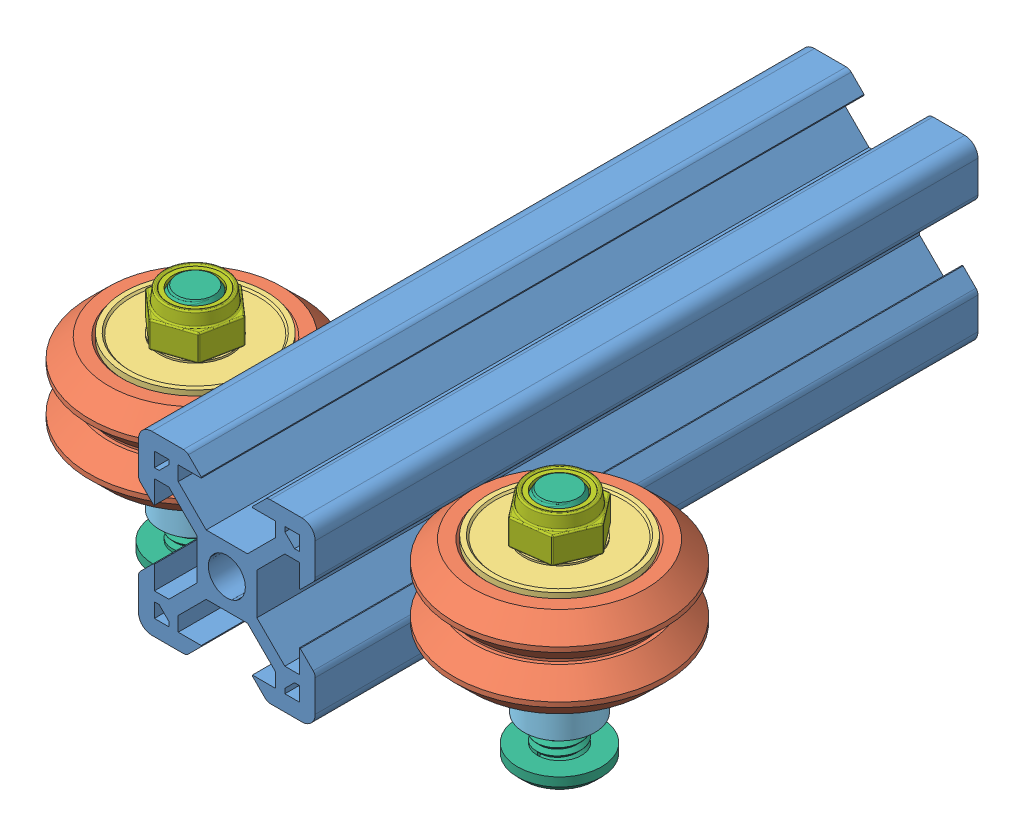
SolidWorks assembly 20 x 20 with wheels, configuration Default. Lengths in mm.
Overall size (66.47 27.2 75).
17 component instances, 7 part files, 3 mates.
Components (placement in the parent):
- 20mm x 20mm x75mm-1: 20mm x 20mm x75mm [Default<As Machined>] at (-32.4939 -14.3937 64.4255) size (20 20 75)
- V-Slot Delrin Dual Wheel Assembly-1: V-Slot Delrin Dual Wheel Assembly [Default] at (-59.3379 -25.4505 35.7981) x (0.980747 0 -0.195284) z (0 -1 0) size (23.89 23.89 27.2)
  - Delrin Dual V-Wheel-1: Delrin Dual V-Wheel [Default] at (4.1766 13.0717 -11.0846) size (23.89 23.89 10.23)
  - Precision Ball Bearing-1: Precision Ball Bearing [Default] at (4.1766 13.0717 -8.0846) x (0 0 -1) z (1 0 0) size (5 16 16)
  - Precision Ball Bearing-2: Precision Ball Bearing [Default] at (4.1766 13.0717 -14.0846) x (0 0 -1) z (1 0 0) size (5 16 16)
  - 5mm Precision Washer-1: 5mm Precision Washer [Default] at (4.1766 13.0717 -11.5846) x (0 0 1) z (-1 0 0) size (1 10 10)
  - .25 Inch Aluminum Spacer-1: .25 Inch Aluminum Spacer [Default] at (4.1766 13.0717 0.7654) x (0 0 -1) z (1 0 0) size (6.35 8 8)
  - 5mm Low Profile Socket Head Screw - Multiple Lengths-1: 5mm Low Profile Socket Head Screw - Multiple Lengths [Default] at (4.1766 13.0717 5.5154) x (0 0 -1) z (1 0 0) size (27.2 9.5 9.5)
  - Nylon Insert Hex Locknut 5mm-1: Nylon Insert Hex Locknut 5mm [Default] at (4.1766 13.0717 -16.5846) x (-0.923728 -0.383049 0) z (0 0 -1) size (7.68 8.82 4.5)
- V-Slot Delrin Dual Wheel Assembly-2: V-Slot Delrin Dual Wheel Assembly [Default] at (-16.3927 -25.4505 33.9845) x (1 0 0) z (0 -1 0) size (23.89 23.89 27.2)
  - Delrin Dual V-Wheel-1: Delrin Dual V-Wheel [Default] at (4.1766 13.0717 -11.0846) size (23.89 23.89 10.23)
  - Precision Ball Bearing-1: Precision Ball Bearing [Default] at (4.1766 13.0717 -8.0846) x (0 0 -1) z (1 0 0) size (5 16 16)
  - Precision Ball Bearing-2: Precision Ball Bearing [Default] at (4.1766 13.0717 -14.0846) x (0 0 -1) z (1 0 0) size (5 16 16)
  - 5mm Precision Washer-1: 5mm Precision Washer [Default] at (4.1766 13.0717 -11.5846) x (0 0 1) z (-1 0 0) size (1 10 10)
  - .25 Inch Aluminum Spacer-1: .25 Inch Aluminum Spacer [Default] at (4.1766 13.0717 0.7654) x (0 0 -1) z (1 0 0) size (6.35 8 8)
  - 5mm Low Profile Socket Head Screw - Multiple Lengths-1: 5mm Low Profile Socket Head Screw - Multiple Lengths [Default] at (4.1766 13.0717 5.5154) x (0 0 -1) z (1 0 0) size (27.2 9.5 9.5)
  - Nylon Insert Hex Locknut 5mm-1: Nylon Insert Hex Locknut 5mm [Default] at (4.1766 13.0717 -16.5846) x (-0.923728 -0.383049 0) z (0 0 -1) size (7.68 8.82 4.5)
Mates (geometry in assembly coordinates):
- Parallel2: parallel: line of 20mm x 20mm x75mm-1 through (-32.4939 -14.3937 64.4255) axis (0 0 -1); plane of V-Slot Delrin Dual Wheel Assembly-1/Delrin Dual V-Wheel-1 through (-52.6891 -14.3659 47.8025) normal (0 -1 0)
- Parallel3: parallel: plane of 20mm x 20mm x75mm-1 through (-37.4011 -4.3937 -10.5745) normal (0 1 0); plane of V-Slot Delrin Dual Wheel Assembly-1/Precision Ball Bearing-2 through (-52.6891 -9.0659 47.8025) normal (0 1 0)
- Coincident3: coincident aligned: plane of V-Slot Delrin Dual Wheel Assembly-1/Delrin Dual V-Wheel-1 through (-52.6891 -14.3659 47.8025) normal (0 -1 0); plane of V-Slot Delrin Dual Wheel Assembly-2/Delrin Dual V-Wheel-1 through (-12.2162 -14.3659 47.0562) normal (0 -1 0)
